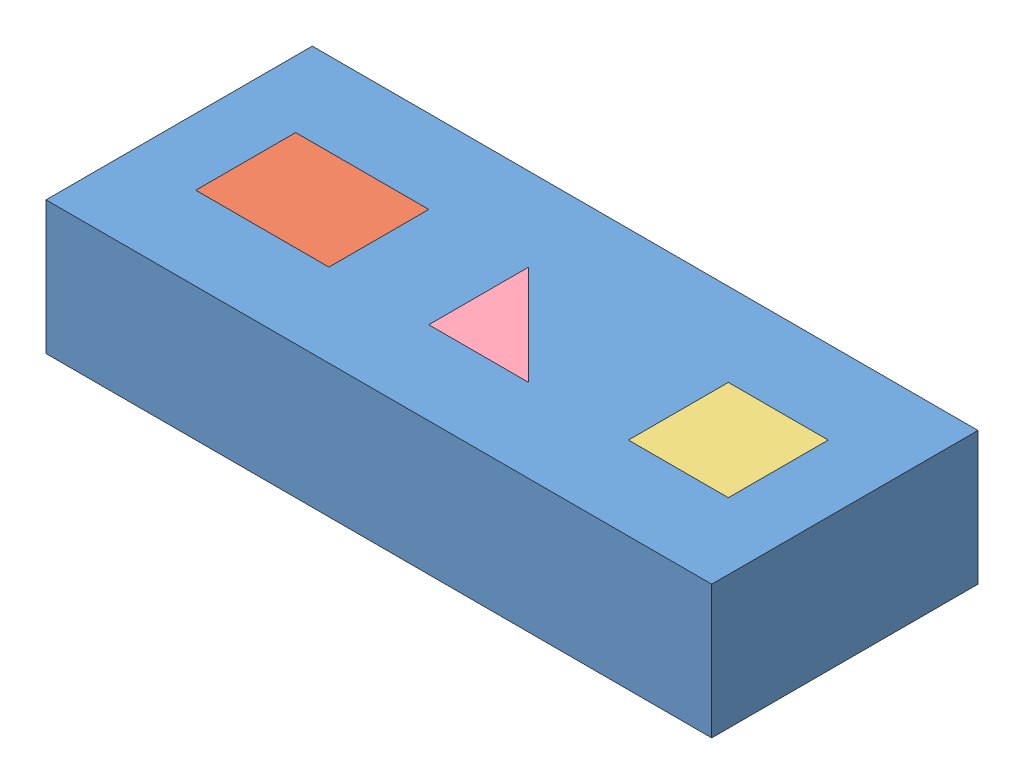
SolidWorks assembly Assem1, configuration Default. Lengths in mm.
Overall size (127 25.4 50.8).
4 component instances, 4 part files, 12 mates.
Components (placement in the parent):
- Block_Coinc_parallel_prepend_2013-1: Block_Coinc_parallel_prepend_2013 [Default] at (-5.3413 56.6943 115.0903) size (127 25.4 50.8)
- rectangle_1_2013-1: rectangle_1_2013 [Default] at (7.3587 56.6943 99.2153) size (25.4 25.4 19.05)
- Square_2013-1: Square_2013 [Default] at (89.9087 56.6943 99.2153) size (19.05 25.4 19.05)
- Traingle_2013-1: Traingle_2013 [Default] at (51.8087 56.6943 99.2153) size (19.05 25.4 19.05)
Mates (geometry in assembly coordinates):
- Coincident1: coincident: point of Block_Coinc_parallel_prepend_2013-1; point of rectangle_1_2013-1
- Coincident2: coincident aligned: plane of Block_Coinc_parallel_prepend_2013-1 through (-5.3413 82.0943 115.0903) normal (0 1 0); plane of rectangle_1_2013-1 through (7.3587 82.0943 99.2153) normal (0 1 0)
- Coincident3: coincident: point of Block_Coinc_parallel_prepend_2013-1; point of rectangle_1_2013-1
- Perpendicular1: perpendicular: plane of Block_Coinc_parallel_prepend_2013-1 through (51.8087 56.6943 99.2153) normal (0 0 -1); plane of Traingle_2013-1 through (51.8087 82.0943 80.1653) normal (-1 0 0)
- Parallel1: parallel aligned: plane of Block_Coinc_parallel_prepend_2013-1 through (-5.3413 82.0943 115.0903) normal (0 1 0); plane of Traingle_2013-1 through (51.8087 82.0943 99.2153) normal (0 1 0)
- Coincident6: coincident anti-aligned: line of Block_Coinc_parallel_prepend_2013-1 through (70.8587 56.6943 99.2153) axis (0 1 0); line of Traingle_2013-1 through (70.8587 82.0943 99.2153) axis (0 -1 0)
- Coincident7: coincident aligned: plane of Block_Coinc_parallel_prepend_2013-1 through (-5.3413 82.0943 115.0903) normal (0 1 0); plane of Traingle_2013-1 through (51.8087 82.0943 99.2153) normal (0 1 0)
- Parallel2: parallel: plane of Block_Coinc_parallel_prepend_2013-1 through (108.9587 56.6943 99.2153) normal (-1 0 0); plane of Square_2013-1 through (102.0282 82.0943 99.2153) normal (1 0 0)
- Coincident10: coincident: line of Block_Coinc_parallel_prepend_2013-1 through (89.9087 82.0943 99.2153) axis (1 0 0); line of Square_2013-1 through (89.9087 82.0943 99.2153) axis (1 0 0)
- Perpendicular2: perpendicular: plane of Block_Coinc_parallel_prepend_2013-1 through (-5.3413 82.0943 115.0903) normal (0 1 0); plane of Square_2013-1 through (108.9587 82.0943 99.2153) normal (1 0 0)
- Perpendicular3: perpendicular: plane of Block_Coinc_parallel_prepend_2013-1 through (-5.3413 82.0943 115.0903) normal (0 1 0); plane of Square_2013-1 through (89.9087 82.0943 80.1653) normal (0 0 -1)
- Coincident13: coincident: point of Block_Coinc_parallel_prepend_2013-1; point of Square_2013-1
